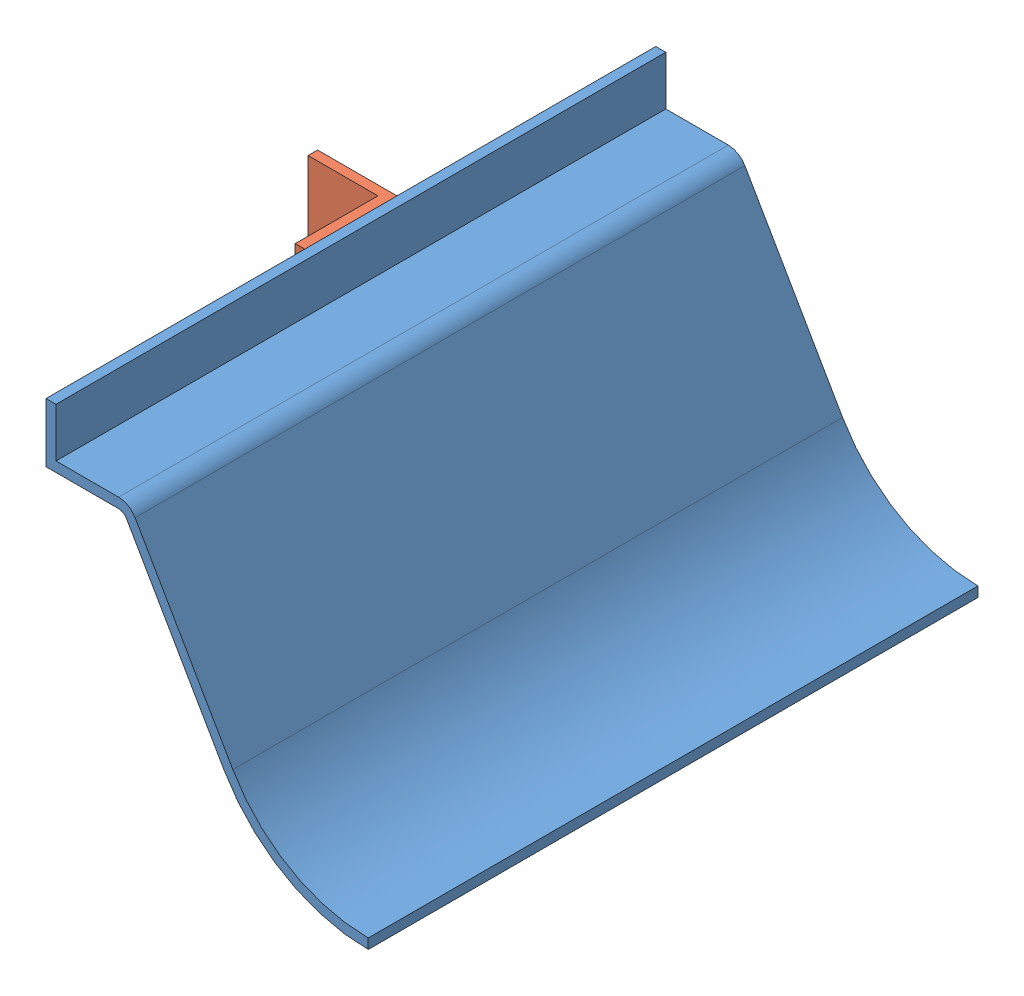
SolidWorks assembly Assem3, configuration Default. Lengths in mm.
Overall size (65.25 51.35 99.06).
2 component instances, 2 part files, 3 mates.
Components (placement in the parent):
- ramp_plate-1: ramp_plate [Default] at (-3.8509 -25.7948 -32.5009) size (52.35 51.35 99.06)
- ramp_brack-1: ramp_brack [Default] at (-56.196 23.9287 24.5221) x (0 0 1) z (0 -1 0) size (14.99 12.9 12.7)
Mates (geometry in assembly coordinates):
- Coincident3: coincident: plane of ramp_plate-1 through (-56.196 23.9287 66.5591) normal (0 1 0); plane of ramp_brack-1 through (-56.196 23.9287 24.5221) normal (0 1 0)
- Coincident4: coincident: plane of ramp_plate-1 through (-56.196 23.9287 66.5591) normal (-1 0 0); plane of ramp_brack-1 through (-56.196 11.2287 9.5361) normal (1 0 0)
- Coincident5: coincident: moEndPointRef_w of ramp_plate-1; moEndPointRef_w of ramp_brack-1
